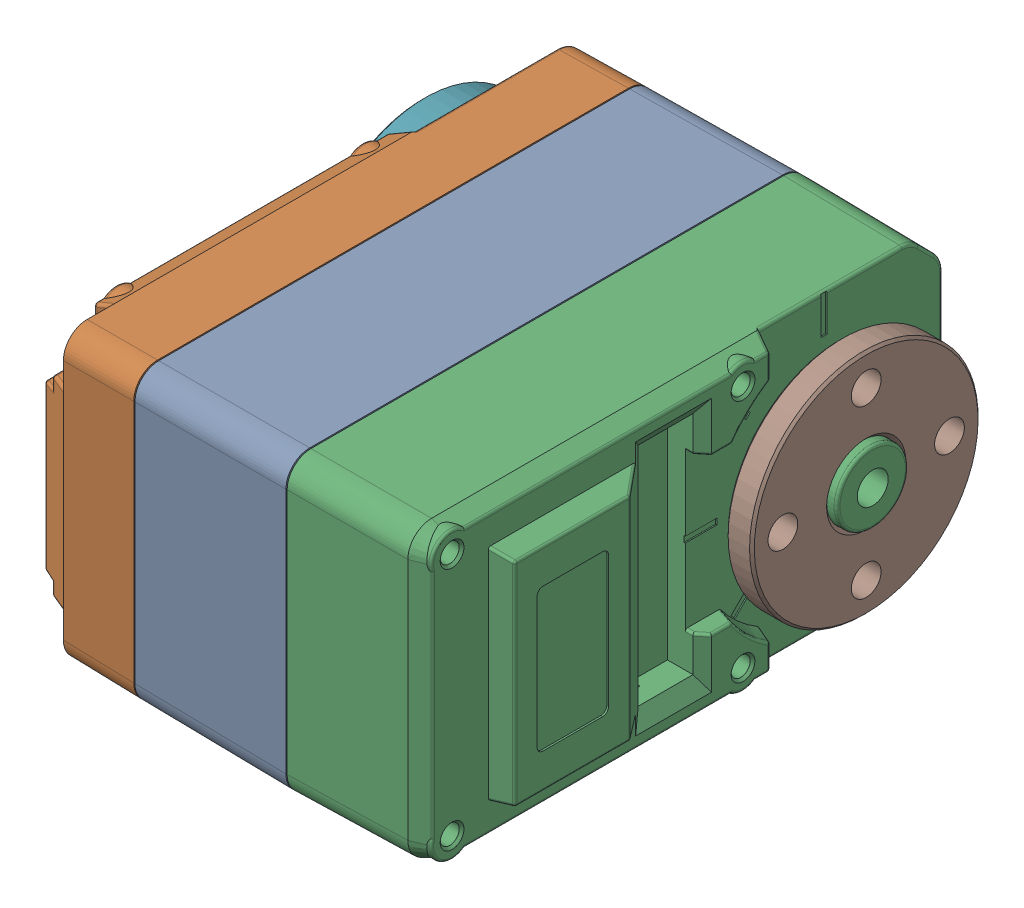
SolidWorks assembly ST3215_4, configuration Default. Lengths in mm.
Overall size (37.8 24.72 45.22).
8 component instances, 8 part files, 0 mates.
Components (placement in the parent):
- ZK_122-1: ZK_122 [Default] at (16.4502 -120.2741 -92.472) x (0 0 1) z (0 -1 0) size (45.22 13.9 24.72)
- SG-ZIJI_15-1: SG-ZIJI_15 [Default] at (16.4502 -120.2741 -92.472) x (0 0 1) z (0 -1 0) size (45 9.77 24.5)
- XG-ZIJI_16-1: XG-ZIJI_16 [Default] at (16.4502 -120.2741 -92.472) x (0 0 1) z (0 -1 0) size (45.22 14.1 24.72)
- MOTOR-1723_3-1: MOTOR-1723_3 [Default] at (39.3002 -119.0241 -92.472) x (0 1 0) z (0 0 1) size (17.05 30.5 17.05)
- PCB-CHAZUO_92-1: PCB-CHAZUO_92 [Default] at (16.4502 -120.2741 -92.472) x (0 0 1) z (0 -1 0) size (28.8 7.2 21.1)
- GE_27-1: GE_27 [Default] at (22.4502 -120.2741 -117.972) x (0 0 1) z (1 0 0) size (17.6 17.59 18.3)
- 金属舵盘（驱动）-1: 金属舵盘（驱动） [Default] at (33.8502 -120.2741 -127.972) x (0 0 1) z (0 -1 0) size (19.2 4.5 19.2)
- 金属舵盘（从动）-1: 金属舵盘（从动） [Default] at (65.9002 -120.2741 -107.972) x (0 0 -1) z (0 -1 0) size (19.2 3.35 19.2)
